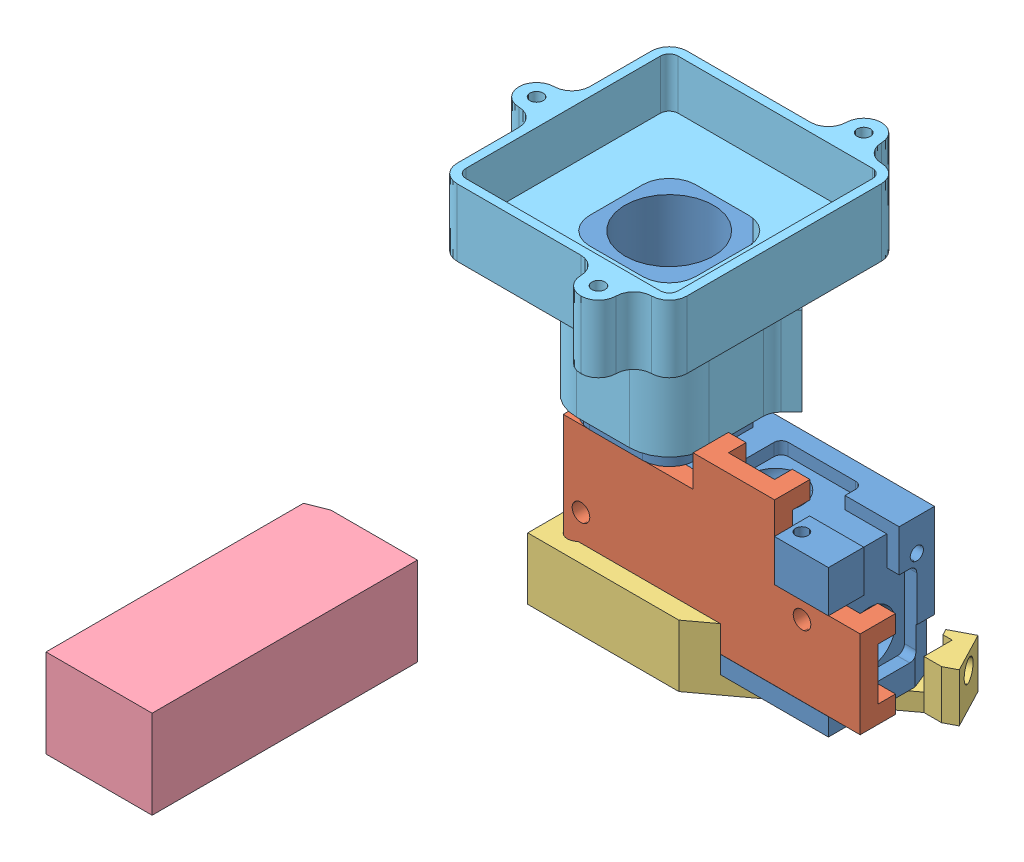
SolidWorks assembly Assem1, configuration Default. Lengths in mm.
Overall size (23.44 21.1 34.45).
5 component instances, 5 part files, 9 mates.
Components (placement in the parent):
- MS_MainBodyv3.2-1: MS_MainBodyv3.2 [Default] at (5.4856 0.7378 13.5478) size (15 17.3 6)
- FilterCover-1: FilterCover [Default] at (-82.5871 11.7639 15.5393) size (16.79 9.09 2)
- MS_Baseplatev3-1: MS_Baseplatev3 [Default] at (5.7356 -0.2622 13.7978) x (0 0 1) z (-1 0 0) size (8.46 3.5 18.16)
- MS_CAPv3-1: MS_CAPv3 [Default] at (-5.3039 0.7378 31.9982) x (0 0 -1) z (1 0 0) size (15 5 6)
- MS_FocusSliderv3.2-1: MS_FocusSliderv3.2 [Default] at (0.9856 10.0378 13.5478) size (15 10.8 17)
Mates (geometry in assembly coordinates):
- Concentric1: concentric anti-aligned: circle of MS_MainBodyv3.2-1; circle of FilterCover-1
- Concentric2: concentric anti-aligned: circle of MS_MainBodyv3.2-1; circle of FilterCover-1
- Coincident3: coincident aligned: plane of MS_MainBodyv3.2-1 through (5.4856 18.0378 13.5478) normal (0 1 0); plane of MS_FocusSliderv3.2-1 through (0.9856 18.0378 13.5478) normal (0 1 0)
- Coincident8: coincident anti-aligned: plane of MS_MainBodyv3.2-1 through (3.9856 18.0378 11.7978) normal (1 0 0); plane of MS_FocusSliderv3.2-1 through (3.9856 20.8378 10.5478) normal (-1 0 0)
- Coincident9: coincident anti-aligned: plane of MS_MainBodyv3.2-1 through (12.9856 9.0378 10.5478) normal (0 0 -1); plane of MS_FocusSliderv3.2-1 through (-2.0144 20.8378 10.5478) normal (0 0 1)
- Coincident10: coincident anti-aligned: plane of MS_Baseplatev3-1 through (5.7356 0.7378 13.7978) normal (0 1 0); plane of MS_CAPv3-1 through (-5.3039 0.7378 31.9982) normal (0 -1 0)
- Concentric5: concentric anti-aligned: circle of MS_MainBodyv3.2-1; circle of MS_Baseplatev3-1
- Concentric6: concentric anti-aligned: circle of MS_MainBodyv3.2-1; circle of MS_Baseplatev3-1
- Coincident12: coincident anti-aligned: plane of MS_MainBodyv3.2-1 through (5.4856 0.7378 13.5478) normal (0 -1 0); plane of MS_Baseplatev3-1 through (5.7356 0.7378 13.7978) normal (0 1 0)
